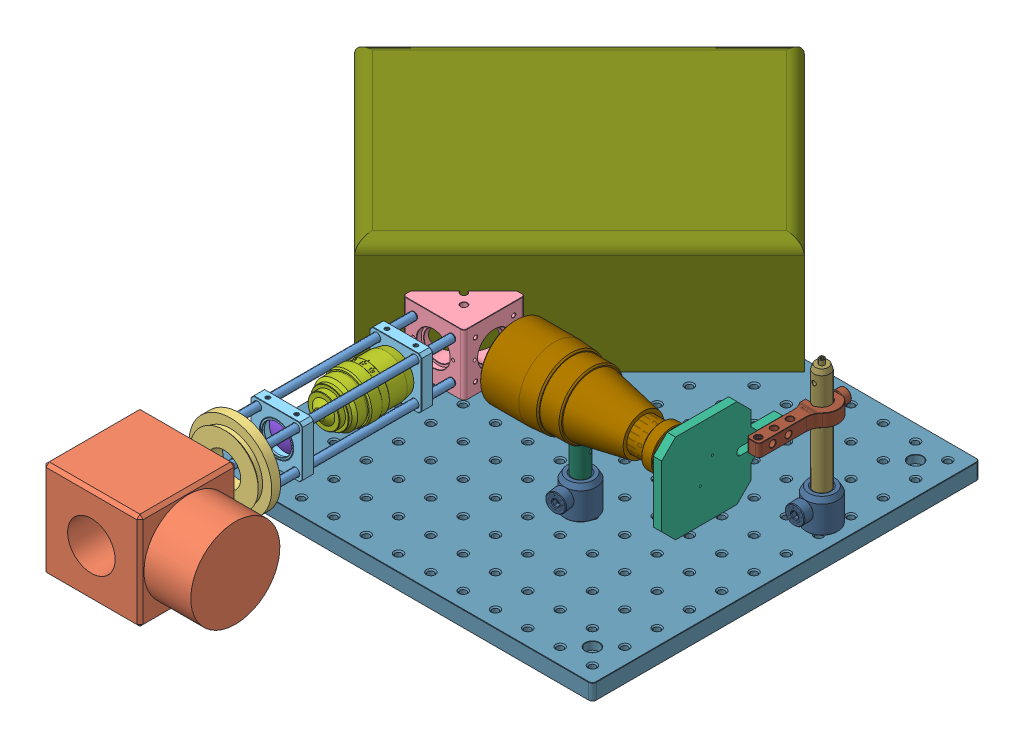
SolidWorks assembly main, configuration Default. Lengths in mm.
Overall size (407.33 137.56 575.81).
31 component instances, 24 part files, 36 mates.
Components (placement in the parent):
- User Library-3002 Series Microscope-1: User Library-3002 Series Microscope [Default] at (74.7086 -61.3272 729.5998) size (252.97 408.49 388.59) (hidden)
  - User Library-3002 Series Microscope_Microscope-Base-1: User Library-3002 Series Microscope_Microscope-Base [Default] at origin size (252.97 269.32 319.18)
  - User Library-3002 Series Microscope_Microscope Binocular-Cover-1: User Library-3002 Series Microscope_Microscope Binocular-Cover [Default] at (0 262.6995 -174.0839) size (67.06 9.02 67.06) (hidden)
  - User Library-3002 Series Microscope_cap holding screw-1: User Library-3002 Series Microscope_cap holding screw [Default] at (-50.5232 255.016 -174.0839) x (0 0 1) z (-1 0 0) size (9 9 44.36)
  - User Library-3002 Series Microscope_Recept_Power-Inlet_2-1: User Library-3002 Series Microscope_Recept_Power-Inlet_2 [Default] at (-8.255 13.2751 1.2314) x (-1 0 0) z (0 0.0971 0.995275) size (50.04 22.35 22.93)
  - User Library-3002 Series Microscope_Binocular Viewing Head-1: User Library-3002 Series Microscope_Binocular Viewing Head [Default] at (0 318.318 -268.8309) x (1 0 0) z (0 -0.493606 0.869686) size (115.32 109.86 202.48)
    - User Library-3002 Series Microscope_EYEPIECE-ROT-1: User Library-3002 Series Microscope_EYEPIECE-ROT [Default] x (-1 0 0) z (0 0 -1) size (42.04 42.04 82.55)
    - User Library-3002 Series Microscope_EYEPIECE-L-1: User Library-3002 Series Microscope_EYEPIECE-L [Default] at (0 0 62.23) x (0 0 -1) z (0 -1 0) size (99.44 78.74 42.16)
    - User Library-3002 Series Microscope_EYEPIECE-R-1: User Library-3002 Series Microscope_EYEPIECE-R [Default] at (0 0 62.23) x (0 0 -1) z (0 1 0) size (99.44 78.74 42.16)
    - User Library-3002 Series Microscope_BINOCULAR-BASE-1: User Library-3002 Series Microscope_BINOCULAR-BASE [Default] at (0 -3.4511 108.7845) x (1 0 0) z (0 0.493606 0.869686) size (95.64 64.39 109.12)
- ER6-P4-Solidworks-1: ER6-P4-Solidworks [Default] at (-227.9808 33.5349 606.9967) x (-0.008727 -0.999962 0) z (0.999962 -0.008727 0) size (5.99 157.48 5.99)
- ER6-P4-Solidworks-2: ER6-P4-Solidworks [Default] at (-227.9715 5.6765 602.0249) x (0 1 0) z (1 0 0) size (5.99 157.48 5.99)
- ER6-P4-Solidworks-3: ER6-P4-Solidworks [Default] at (-197.9715 5.6765 602.0249) x (0 1 0) z (1 0 0) size (5.99 157.48 5.99)
- ER6-P4-Solidworks-4: ER6-P4-Solidworks [Default] at (-200.6321 34.8369 602.0249) x (-0.78596 -0.618278 0) z (-0.618278 0.78596 0) size (5.99 157.48 5.99)
- Zeiss-Dual-Lamphouse-1: Zeiss-Dual-Lamphouse [Default] at (-2024.6734 19.6106 758.8119) size (113.15 76.33 76.33)
- SM1A23-Zeiss-Lamphouse-1: SM1A23-Zeiss-Lamphouse [Default] at (-214.0979 19.6106 692.7108) x (-1 0 0) z (0 0 -1) size (65 65 12)
- KCB1_M-Solidworks-1: KCB1_M-Solidworks [Default] at (-214.0978 19.6106 504.1808) x (-1 -0.000004 0) z (0 0 -1) size (48.26 48.26 48.26)
- CP02-Solidworks-1: CP02-Solidworks [Default] at (-214.0979 19.6106 646.979) x (0 -1 0) z (0 0 1) size (41.4 40.64 8.89)
- CP02-Solidworks-2: CP02-Solidworks [Default] at (-214.0979 19.6106 553.3323) x (0 -1 0) z (0 0 1) size (41.4 40.64 8.89)
- LED-Mount-Post-1: LED-Mount-Post [Default] at (-30.1933 37.8373 484.59) x (-0.000004 1 0) z (1 0.000004 0) size (70 100 6.6)
- Nikon-1: Nikon [Default] at (-214.0979 19.6106 617.8373) x (1 0 0) z (0 1 0) size (37.5 65.06 37.5)
- LB1761-B-Solidworks-1: LB1761-B-Solidworks [Default] at (-214.0979 19.6106 643.4804) x (0.991266 0.131878 0) z (0 0 1) size (25.4 25.4 8.98)
- BE10M-A-Solidworks-1: BE10M-A-Solidworks [Default] at (-72.9405 19.6112 504.1808) x (0 0 1) z (-1 -0.000004 0) size (56 56 123.65)
- PH1-Solidworks-1: PH1-Solidworks [Default] at (-18.513 -43.5843 418.4155) x (0.99803 0.000004 -0.062738) z (0.062738 0 0.99803) size (25 26.01 35.41)
- PMTR_M-Solidworks-1: PMTR_M-Solidworks [Default] at (46.4156 -3.6154 426.0308) x (0 0 1) z (-1 -0.000004 0) size (73.15 10.7 20.07)
- TR4-Solidworks-1: TR4-Solidworks [Default] at (-18.5129 -49.4263 418.4155) x (1 0.000004 0) z (0 0 1) size (12.67 105.8 12.87)
- M405D2-Solidworks-1: M405D2-Solidworks [Default] at (-25.2932 19.4943 504.663) x (0 -0.000004 1) z (-1 -0.000004 0) size (22.02 21.78 3.8)
- MB12-Solidworks-1: MB12-Solidworks [Default] at (-151.3904 -68.9849 465.8573) x (1 0.000004 0) z (0 0 1) size (304.8 12.7 304.8)
- PH1-Solidworks-2: PH1-Solidworks [Default] at (-122.4402 -43.5847 504.1808) x (0.990828 0.000004 -0.135128) z (0.135128 0.000001 0.990828) size (25 26.01 35.41)
- TR2-Solidworks-1: TR2-Solidworks [Default] at (-122.4402 -55.289 504.1808) x (0.342233 0.000001 0.939615) z (-0.939615 -0.000004 0.342233) size (12.67 55 12.87)
- Projector-1: Projector [Default] at (26.5664 23.849 101.9368) x (0.707107 0.000003 -0.707107) z (0.707107 0.000001 0.707107) size (250 89.45 193.58)
Mates (geometry in assembly coordinates):
- Coincident5: coincident anti-aligned: plane of SM1A23-Zeiss-Lamphouse-1 through (-214.0979 19.6106 680.7108) normal (0 0 -1); plane of ER6-P4-Solidworks-2 through (-229.0979 4.6106 680.7108) normal (0 0 1)
- Coincident6: coincident anti-aligned: plane of SM1A23-Zeiss-Lamphouse-1 through (-214.0979 19.6106 680.7108) normal (0 0 -1); plane of ER6-P4-Solidworks-1 through (-229.1218 31.8675 680.7108) normal (0 0 1)
- Coincident7: coincident anti-aligned: plane of SM1A23-Zeiss-Lamphouse-1 through (-214.0979 19.6106 680.7108) normal (0 0 -1); plane of ER6-P4-Solidworks-4 through (-199.0979 34.6106 680.7108) normal (0 0 1)
- Coincident8: coincident anti-aligned: plane of SM1A23-Zeiss-Lamphouse-1 through (-214.0979 19.6106 680.7108) normal (0 0 -1); plane of ER6-P4-Solidworks-3 through (-199.0979 4.6106 680.7108) normal (0 0 1)
- Concentric2: concentric aligned: circle of ER6-P4-Solidworks-2; circle of SM1A23-Zeiss-Lamphouse-1
- Concentric3: concentric aligned: circle of ER6-P4-Solidworks-1; circle of SM1A23-Zeiss-Lamphouse-1
- Concentric4: concentric anti-aligned: circle of ER6-P4-Solidworks-4; circle of SM1A23-Zeiss-Lamphouse-1
- Concentric5: concentric anti-aligned: circle of ER6-P4-Solidworks-3; circle of SM1A23-Zeiss-Lamphouse-1
- Concentric13: concentric aligned: cylinder of ER6-P4-Solidworks-4 through (-199.0979 34.6106 680.7108) axis (0 0 1) radius 2.9972; cylinder of CP02-Solidworks-1 through (-199.0979 34.6106 642.534) axis (0 0 1) radius 3.0099
- Concentric14: concentric aligned: circle of KCB1_M-Solidworks-1; circle of CP02-Solidworks-1
- Concentric15: concentric aligned: cylinder of ER6-P4-Solidworks-3 through (-199.0979 4.6106 680.7108) axis (0 0 1) radius 2.9972; cylinder of CP02-Solidworks-1 through (-199.0979 4.6106 642.534) axis (0 0 1) radius 3.0099
- Coincident11: coincident anti-aligned: plane of ER6-P4-Solidworks-4 through (-201.2539 32.9146 528.3108) normal (0 0 -1); plane of KCB1_M-Solidworks-1 through (-238.2279 43.7405 528.3108) normal (0 0 1)
- Concentric16: concentric anti-aligned: circle of CP02-Solidworks-2; circle of Nikon-1
- Coincident13: coincident anti-aligned: plane of CP02-Solidworks-2 through (-258.9433 19.6106 557.7773) normal (0 0 1); plane of Nikon-1 through (-200.5979 19.6106 557.7773) normal (0 0 -1)
- Concentric17: concentric aligned: cylinder of ER6-P4-Solidworks-3 through (-199.0979 4.6106 680.7108) axis (0 0 1) radius 2.9972; cylinder of CP02-Solidworks-2 through (-199.0979 4.6106 548.8873) axis (0 0 1) radius 3.0099
- Concentric18: concentric anti-aligned: circle of CP02-Solidworks-1; circle of LB1761-B-Solidworks-1
- Concentric19: concentric anti-aligned: circle of KCB1_M-Solidworks-1; circle of BE10M-A-Solidworks-1
- Concentric20: concentric aligned: circle of LED-Mount-Post-1; circle of BE10M-A-Solidworks-1
- Concentric24: concentric anti-aligned: cylinder of PMTR_M-Solidworks-1 through (-18.5133 27.1114 418.4155) axis (0.000004 -1 0) radius 6.35; cylinder of TR4-Solidworks-1 through (-18.5134 52.1737 418.4155) axis (-0.000004 1 0) radius 6.3373
- Concentric25: concentric aligned: circle of PH1-Solidworks-1; cylinder of TR4-Solidworks-1 through (-18.5134 52.1737 418.4155) axis (-0.000004 1 0) radius 6.3373
- Coincident14: coincident anti-aligned: plane of PH1-Solidworks-1 through (-18.5129 -49.4263 418.4155) normal (-0.000004 1 0); plane of TR4-Solidworks-1 through (-12.6836 -49.4263 418.4155) normal (0.000004 -1 0)
- Coincident15: coincident anti-aligned: plane of LED-Mount-Post-1 through (-23.5933 39.6114 484.1808) normal (1 0.000004 0); plane of PMTR_M-Solidworks-1 through (-23.5933 27.1114 435.6893) normal (-1 -0.000004 0)
- Concentric26: concentric aligned: circle of Zeiss-Dual-Lamphouse-1; cone of SM1A23-Zeiss-Lamphouse-1 through (-214.0979 19.6106 691.1399) axis (0 0 -1)
- Parallel3: parallel anti-aligned: line of Zeiss-Dual-Lamphouse-1 through (-249.7629 55.2756 720.6469) axis (1 0 0); line of SM1A23-Zeiss-Lamphouse-1 through (-199.0979 34.6106 680.7108) axis (-1 0 0)
- Concentric27: concentric: cylinder of ER6-P4-Solidworks-1 through (-229.0979 34.6106 528.3108) axis (0 0 -1) radius 2.9972; cylinder of CP02-Solidworks-2 through (-229.0978 34.6106 548.8873) axis (0 0 1) radius 3.0099
- Concentric28: concentric aligned: cylinder of ER6-P4-Solidworks-4 through (-199.0979 34.6106 680.7108) axis (0 0 1) radius 2.9972; cylinder of KCB1_M-Solidworks-1 through (-199.0979 34.6106 528.3108) axis (0 0 1) radius 1.4224
- Parallel5: parallel aligned: line of KCB1_M-Solidworks-1 through (-190.2219 43.7407 525.7708) axis (0 0 -1); line of LED-Mount-Post-1 through (-30.1934 54.6113 528.3229) axis (0 0 -1)
- Coincident17: coincident anti-aligned: plane of CP02-Solidworks-1 through (-258.9433 19.6106 642.534) normal (0 0 -1); circle of LB1761-B-Solidworks-1
- Coincident18: coincident aligned: plane of LED-Mount-Post-1 through (9.9478 27.1115 484.59) normal (-0.000004 1 0); plane of PMTR_M-Solidworks-1 through (-18.5133 27.1114 417.9075) normal (-0.000004 1 0)
- Coincident19: coincident anti-aligned: plane of LED-Mount-Post-1 through (-25.2933 37.8373 484.59) normal (-1 -0.000004 0); plane of M405D2-Solidworks-1 through (-25.2932 12.7443 502.413) normal (1 0.000004 0)
- Coincident20: coincident anti-aligned: plane of PH1-Solidworks-1 through (-46.0999 -56.2844 420.1497) normal (0.000004 -1 0); plane of MB12-Solidworks-1 through (-300.7904 -56.2855 615.2573) normal (-0.000004 1 0)
- Concentric29: concentric anti-aligned: circle of BE10M-A-Solidworks-1; circle of TR2-Solidworks-1
- Parallel6: parallel anti-aligned: plane of MB12-Solidworks-1 through (-300.7904 -56.2855 615.2573) normal (-0.000004 1 0); plane of TR2-Solidworks-1 through (-120.4452 -55.289 509.6581) normal (0.000004 -1 0)
- Concentric30: concentric anti-aligned: cylinder of PH1-Solidworks-2 through (-122.4403 -30.8847 504.1808) axis (0.000004 -1 0) radius 6.3881; cylinder of TR2-Solidworks-1 through (-122.4404 -4.489 504.1808) axis (-0.000004 1 0) radius 6.3373
- Coincident21: coincident anti-aligned: plane of MB12-Solidworks-1 through (-300.7904 -56.2855 615.2573) normal (-0.000004 1 0); plane of PH1-Solidworks-2 through (-149.8281 -56.2848 507.9159) normal (0.000004 -1 0)
- Coincident22: coincident anti-aligned: plane of BE10M-A-Solidworks-1 through (-72.9394 -4.4888 489.1808) normal (0.000004 -1 0); plane of TR2-Solidworks-1 through (-122.4404 -4.489 504.1808) normal (-0.000004 1 0)
